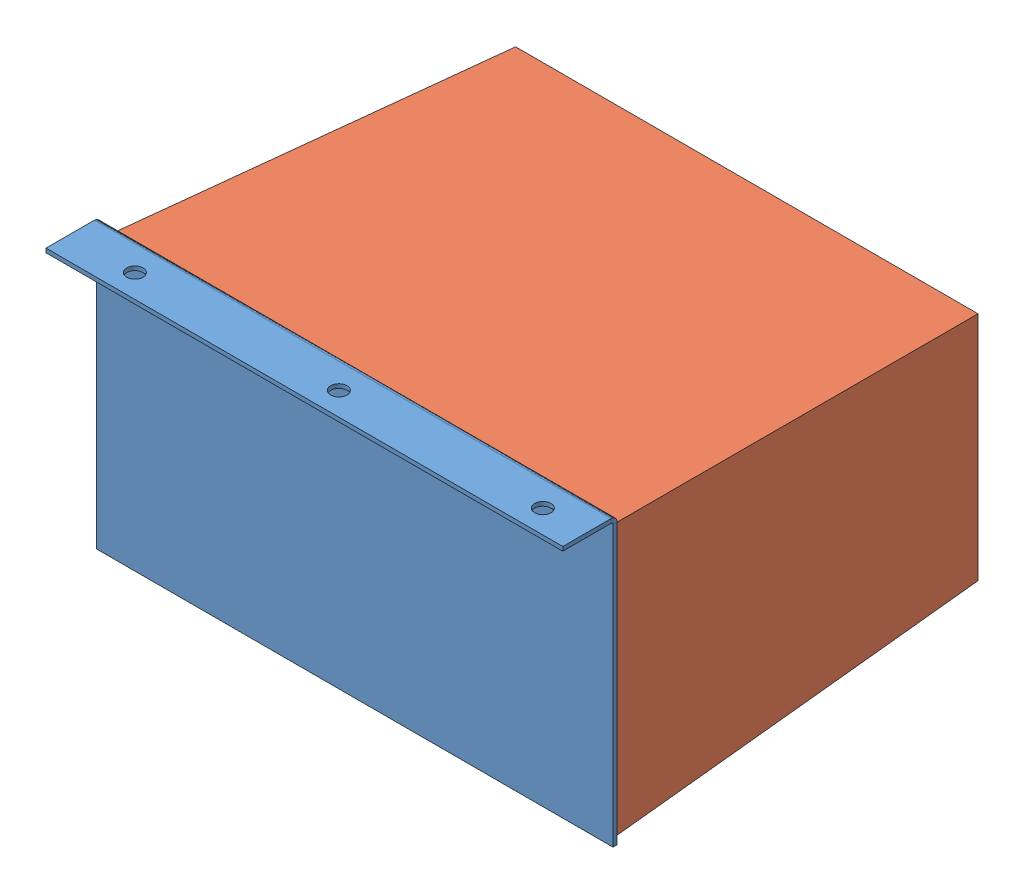
SolidWorks assembly Assem1, configuration Default. Lengths in mm.
Overall size (190 105 160).
2 component instances, 2 part files, 3 mates.
Components (placement in the parent):
- oil_cap-1: oil_cap [Default] at (111.3871 123.0572 106.0299) size (190 105 20)
- oil_tank-1: oil_tank [Default] at (91.6048 115.5605 104.5299) x (-1 0 0) z (0 0 -1) size (184.67 99.67 140)
Mates (geometry in assembly coordinates):
- Coincident1: coincident: plane of oil_cap-1 through (111.3871 123.0572 104.5299) normal (0 0 -1); plane of oil_tank-1 through (91.6048 115.5605 104.5299) normal (0 0 1)
- Coincident2: coincident: line of oil_cap-1 through (9.2819 169.5925 104.5299) axis (1 0 0); line of oil_tank-1 through (199.2819 169.5925 104.5299) axis (-1 0 0)
- Coincident3: coincident aligned: line of oil_cap-1 through (199.2819 66.8291 104.5299) axis (0 1 0); line of oil_tank-1 through (199.2819 69.9184 104.5299) axis (0 1 0)
